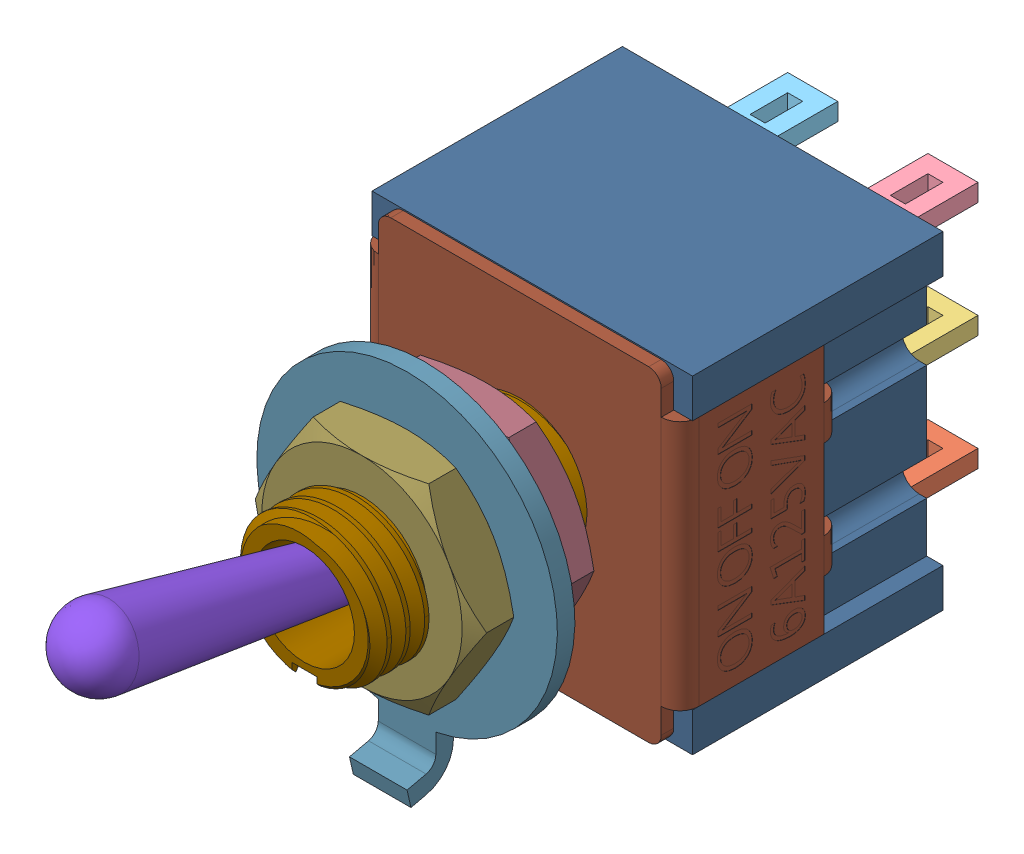
SolidWorks assembly ToggleSwitch 6Pin.stp, configuration Default. Lengths in mm.
Overall size (12.8 14.55 33.21).
14 component instances, 14 part files, 0 mates.
Components (placement in the parent):
- Washer.stp-1: Washer.stp [Default] at (0 0 3.95) size (10 10 0.7)
- PIN_1of6.stp-1: PIN_1of6.stp [Default] at origin size (2.2 0.7 4)
- PIN_2of6.stp-1: PIN_2of6.stp [Default] at origin size (2.2 0.7 4)
- PIN_3of6.stp-1: PIN_3of6.stp [Default] at origin size (2.2 0.7 4)
- PIN_4of6.stp-1: PIN_4of6.stp [Default] at origin size (2.2 0.7 4)
- PIN_5of6.stp-1: PIN_5of6.stp [Default] at origin size (2.2 0.7 4)
- PIN_6of6.stp-1: PIN_6of6.stp [Default] at origin size (2.2 0.7 4)
- Batton Clone 1.stp-1: Batton Clone 1.stp [Default] at (0 0 5.3679) x (1 0 0) z (0 0.218143 0.975917) size (4 4 18.73)
- Thread.stp-1: Thread.stp [Default] at (0 0 -0.5) size (6.03 5.78 9.6)
- Plastic Body.stp-1: Plastic Body.stp [Default] at origin size (12.8 13.1 10.5)
- Sheetmatal Frame.stp-1: Sheetmatal Frame.stp [Default] at (0 0 0.5) size (12.8 13 7.7)
- Nut M6x0.75mm  clone.stp-1: Nut M6x0.75mm  clone.stp [Default] at (0 0 5.9) size (9.24 8 1.8)
- Nut M6x0.75mm.stp-1: Nut M6x0.75mm.stp [Default] at (0 0 2.7) size (9.24 8 1.8)
- Washer Anti Twist Protection.stp-1: Washer Anti Twist Protection.stp [Default] at (0 0 4.65) size (12 14 1.85)
